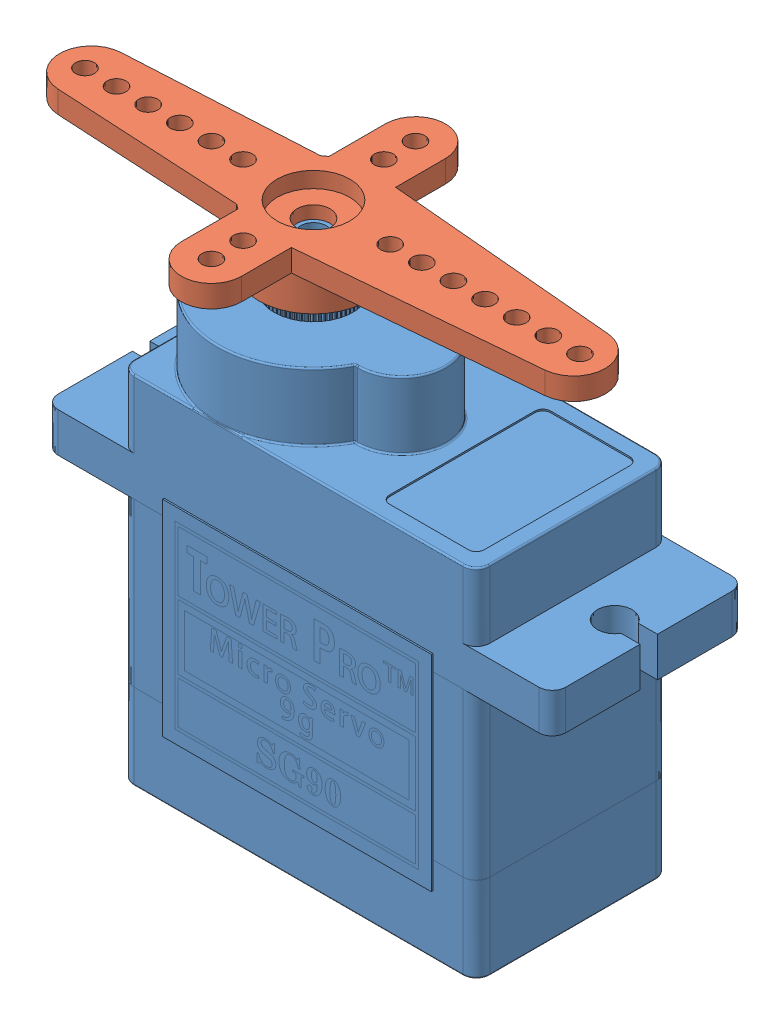
SolidWorks assembly SG90 - Micro Servo Assembly Socle, configuration Default. Lengths in mm.
Overall size (37.25 31.75 16.7).
2 component instances, 2 part files, 2 mates.
Components (placement in the parent):
- SG90 - Micro Servo 9g - Tower Pro.1-2: SG90 - Micro Servo 9g - Tower Pro.1 [Peça] at origin size (32.1 29.95 12.4)
- SG90 - Micro Servo 9g - Tower Pro.4-1: SG90 - Micro Servo 9g - Tower Pro.4 [Peça] at (-5.15 21.1 0) size (34.5 3.8 16.7)
Mates (geometry in assembly coordinates):
- Coïncidente1: coincident anti-aligned: plane of SG90 - Micro Servo 9g - Tower Pro.1-2 through (-5.15 19.3 0) normal (0 1 0); plane of SG90 - Micro Servo 9g - Tower Pro.4-1 through (-5.15 19.3 0) normal (0 -1 0)
- Coaxiale1: concentric anti-aligned: circle of SG90 - Micro Servo 9g - Tower Pro.1-2; circle of SG90 - Micro Servo 9g - Tower Pro.4-1
